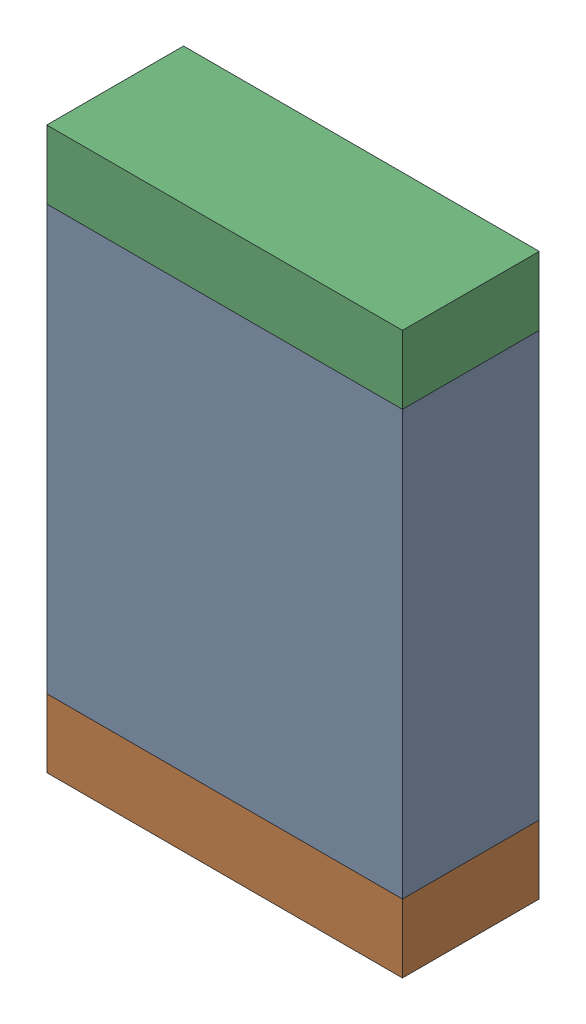
SolidWorks assembly C97, configuration Default. Lengths in mm.
Overall size (1.3 2.05 0.5).
6 component instances, 2 part files, 0 mates.
Components (placement in the parent):
- 836753008-1: 836753008 [Default] at (110.15 70.475 0) size (1.3 1.55 0.5)
  - Extruded_23-1: Extruded_23 [Default] at origin size (1.3 1.55 0.5)
- 836753264-1: 836753264 [Default] at (110.15 69.575 0) size (1.3 0.25 0.5)
  - Extruded_22-1: Extruded_22 [Default] at origin size (1.3 0.25 0.5)
- 836753264-2: 836753264 [Default] at (110.15 71.375 0) size (1.3 0.25 0.5)
  - Extruded_22-1: Extruded_22 [Default] at origin size (1.3 0.25 0.5)
